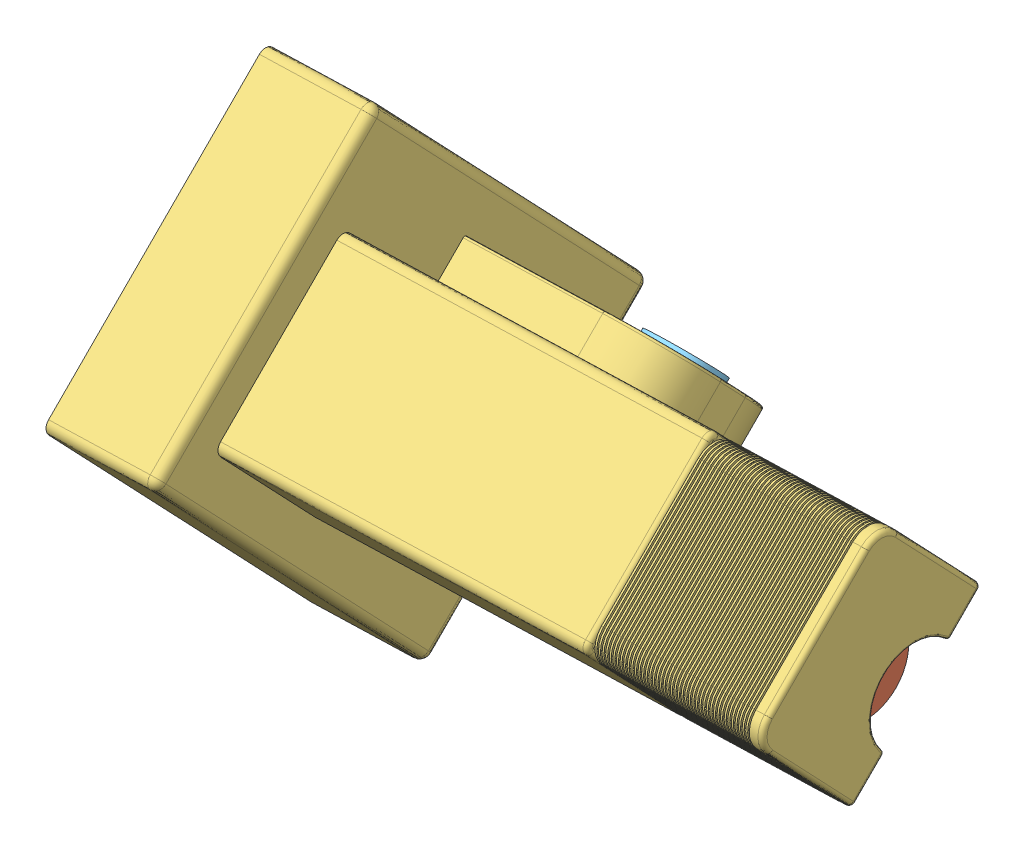
SolidWorks assembly Engine, configuration Default. Lengths in mm.
Overall size (149.64 114.02 109.32).
5 component instances, 5 part files, 8 mates.
Components (placement in the parent):
- Part4-1: Part4 [Default] at (138.6703 114.7098 -16.9031) x (-0.794261 -0.451848 -0.40618) z (0.607253 -0.568554 -0.554969) size (67.71 7.22 21.43)
- Part5-1: Part5 [Default] at (154.2733 123.4311 -17.7313) x (0.046309 -0.724699 -0.687508) z (-0.99873 -0.047249 -0.017467) size (19.76 19.76 19.9)
- Part7-1: Part7 [Default] at (45.4767 149.9354 -11.6151) x (-0.019826 0.687444 -0.725967) z (0.046309 -0.724699 -0.687508) size (69.26 144.65 82.21)
- Part8-1: Part8 [Default] at (116.8154 116.6612 -61.0675) x (0.938287 -0.237973 -0.25097) z (-0.345288 -0.686141 -0.640302) size (44.17 15.48 22.08)
- Part9-1: Part9 [Default] at (80.1714 127.9287 -53.3811) x (0.951161 0.236696 0.198159) z (0.308057 -0.686583 -0.658563) size (15.46 31.5 15.46)
Mates (geometry in assembly coordinates):
- Concentric5: concentric aligned: cylinder of Part5-1 through (155.2303 123.6682 -17.5335) axis (0.99873 0.047249 0.017467) radius 9.8824; cylinder of Part7-1 through (27.1233 117.6075 -19.7739) axis (0.99873 0.047249 0.017467) radius 10
- Concentric7: concentric aligned: cylinder of Part4-1 through (145.8958 124.0839 -18.6005) axis (0.019826 -0.687444 0.725967) radius 2.1824; cylinder of Part5-1 through (145.9413 122.5059 -16.934) axis (0.019826 -0.687444 0.725967) radius 2.5284
- Concentric8: concentric anti-aligned: cylinder of Part4-1 through (106.0812 101.4338 -38.9614) axis (0.019826 -0.687444 0.725967) radius 6.4303; cylinder of Part8-1 through (106.0239 103.4209 -41.0599) axis (-0.019826 0.687444 -0.725967) radius 6.1321
- Concentric9: concentric anti-aligned: cylinder of Part7-1 through (80.194 127.1456 -52.5541) axis (0.019826 -0.687444 0.725967) radius 7.73; cylinder of Part8-1 through (80.6929 109.8454 -34.2844) axis (-0.019826 0.687444 -0.725967) radius 7.728
- Concentric10: concentric anti-aligned: cylinder of Part7-1 through (80.194 127.1456 -52.5541) axis (0.019826 -0.687444 0.725967) radius 7.73; cylinder of Part9-1 through (80.7959 106.2742 -30.5131) axis (-0.019826 0.687444 -0.725967) radius 7.73
- Distance2: distance = 2.0319 mm anti-aligned: plane of Part5-1 through (145.8996 123.9495 -18.4586) normal (0.019826 -0.687444 0.725967); plane of Part4-1 through (145.8594 125.3464 -19.9337) normal (-0.019826 0.687444 -0.725967)
- Distance3: distance = 2.7626 mm aligned: plane of Part4-1 through (106.188 97.7306 -35.0508) normal (0.019826 -0.687444 0.725967); plane of Part8-1 through (106.2427 95.8315 -33.0452) normal (0.019826 -0.687444 0.725967)
- Distance4: distance = 20.3608 mm aligned: plane of Part9-1 through (80.7959 106.2742 -30.5131) normal (0.019826 -0.687444 0.725967); plane of Part7-1 through (26.7406 130.8766 -33.7866) normal (0.019826 -0.687444 0.725967)
